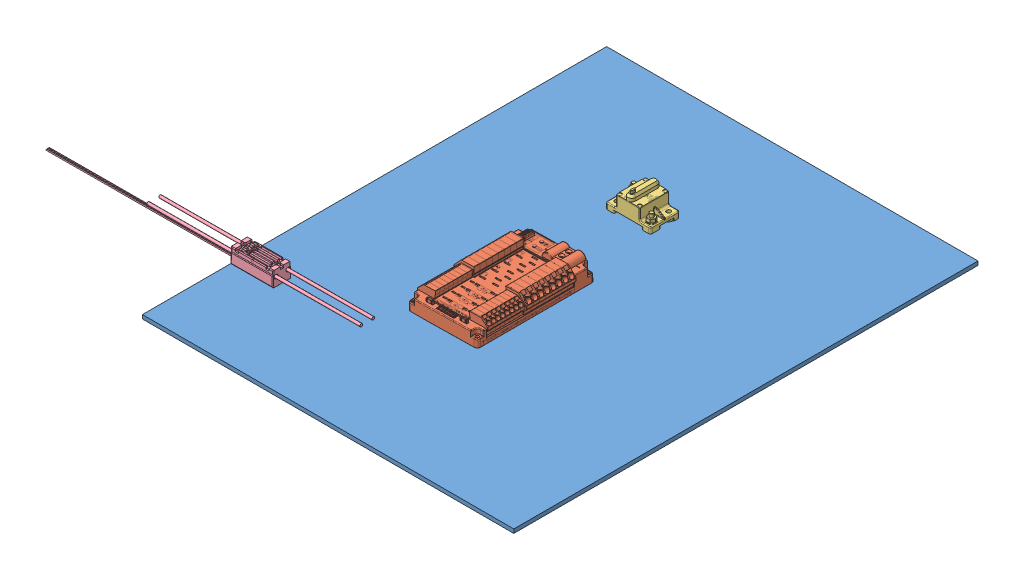
SolidWorks assembly Assem1, configuration Default. Lengths in mm.
Overall size (914.47 48.5 762).
4 component instances, 4 part files, 7 mates.
Components (placement in the parent):
- Test Bench-1: Test Bench [Default] at (-308.9959 0.9682 380.3993) size (609.6 6.35 762)
- PDP-1: PDP [Default] at (-41.0937 14.3617 63.9284) x (0 -0.000628 1) z (-0.999848 -0.017452 -0.000011) size (192.68 36.15 120.93)
- Breaker-1: Breaker [Default] at (-42.473 12.1442 -174.2354) size (73.72 42.2 48.95)
- Speed Controller-1: Speed Controller [Default] at (-274.078 23.1085 221.1265) x (0 0.00003 1) z (0.004363 -0.99999 0.00003) size (30.12 514.63 24.39)
Mates (geometry in assembly coordinates):
- Coincident1: coincident: plane of Test Bench-1 through (-308.9959 7.3182 380.3993) normal (0 1 0); plane of PDP-1 through (-98.3723 6.6229 155.9478) normal (0.017452 -0.999847 -0.000628)
- Parallel1: parallel: plane of Test Bench-1 through (-308.9959 7.3182 380.3993) normal (-1 0 0); plane of PDP-1 through (-98.3723 6.7242 -5.4946) normal (-1 0 0)
- Coincident2: coincident anti-aligned: plane of Test Bench-1 through (-308.9959 7.3182 380.3993) normal (0 1 0); plane of Breaker-1 through (-11.9505 7.3182 -194.6061) normal (0 -1 0)
- Parallel2: parallel aligned: plane of Test Bench-1 through (-308.9959 7.3182 -381.6007) normal (0 0 -1); plane of Breaker-1 through (-42.473 14.6842 -198.3654) normal (0 0 -1)
- Coincident3: coincident: plane of Test Bench-1 through (-308.9959 7.3182 380.3993) normal (0 1 0); plane of Speed Controller-1 through (-274.0098 7.4712 221.1269) normal (0.004363 -0.99999 0.00003)
- Coincident4: coincident: plane of Test Bench-1 through (-308.9959 7.3182 380.3993) normal (0 1 0); plane of Speed Controller-1 through (-274.0098 7.4712 221.1269) normal (0.004363 -0.99999 0.00003)
- Coincident5: coincident: plane of Test Bench-1 through (-308.9959 7.3182 380.3993) normal (-1 0 0); plane of Speed Controller-1 through (-308.9959 21.4057 206.1265) normal (-1 0 0)
